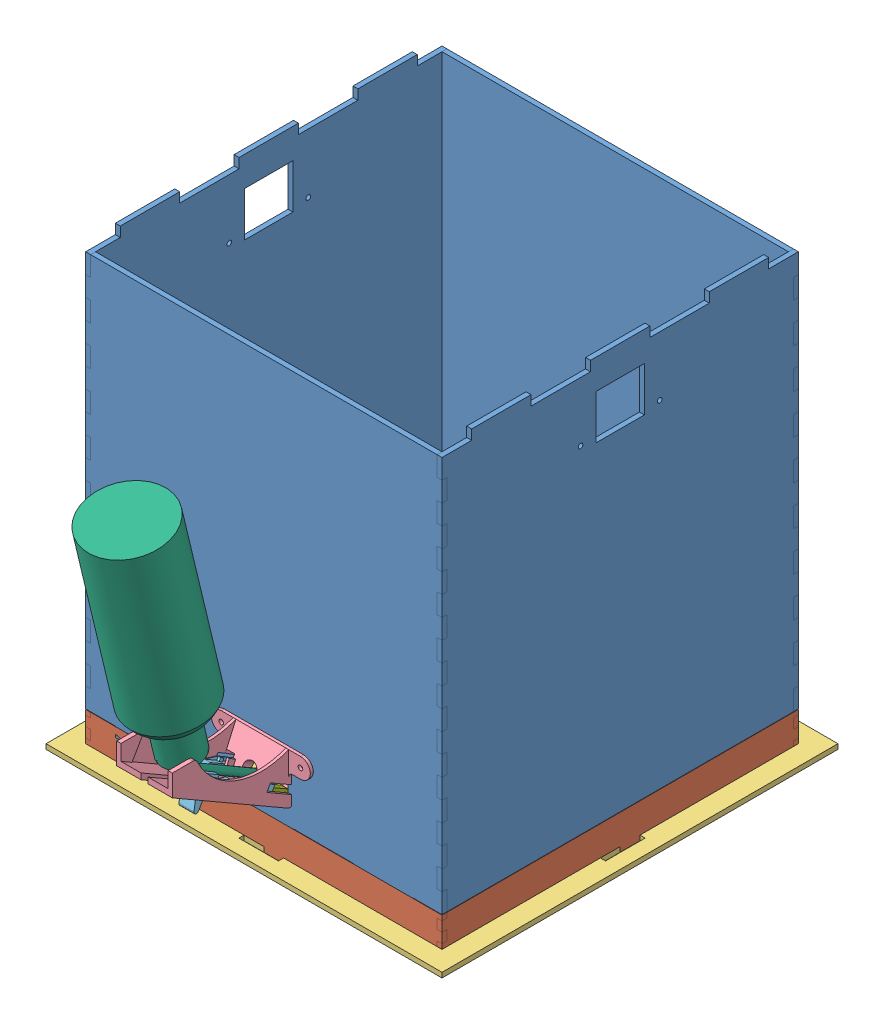
SolidWorks assembly lickometerChamberV2, configuration Default. Lengths in mm.
Overall size (254 282.83 353.42).
16 component instances, 7 part files, 14 mates.
Components (placement in the parent):
- lickometerV2_wallSide-1: lickometerV2_wallSide [Default] at (-35.9898 6.3492 13.4078) size (228.6 260.35 3.17)
- lickometerV2_wallSide-2: lickometerV2_wallSide [Default] at (-35.9898 6.3492 238.8328) size (228.6 260.35 3.17)
- bottomAssemblyV2-1: bottomAssemblyV2 [Default] at (-5.2881 -133.2401 226.0412) size (254 22.23 254)
  - bottomWall-1: bottomWall [Default] at (-30.7017 2.8103 12.7916) size (228.6 22.23 3.17)
  - bottomWall-2: bottomWall [Default] at (80.4233 2.8103 -98.3334) x (0 0 -1) z (1 0 0) size (228.6 22.23 3.17)
  - bottomWall-3: bottomWall [Default] at (-30.7017 2.8103 -209.4584) x (-1 0 0) z (0 0 -1) size (228.6 22.23 3.17)
  - bottomWall-4: bottomWall [Default] at (-141.8267 2.8103 -98.3334) x (0 0 1) z (-1 0 0) size (228.6 22.23 3.17)
  - bottomFloor-1: bottomFloor [Default] at (-30.7017 -6.7147 -98.3334) x (-1 0 0) z (0 0 1) size (254 3.17 254)
- lickometerV2_wallSide-3: lickometerV2_wallSide [Default] at (-147.1148 6.3492 127.7078) x (0 0 -1) z (-1 0 0) size (228.6 260.35 3.17)
- lickometerV2_wallSide-4: lickometerV2_wallSide [Default] at (78.3102 6.3492 127.7078) x (0 0 -1) z (-1 0 0) size (228.6 260.35 3.17)
- bottleMountAssemblyV4.0-1: bottleMountAssemblyV4.0 [Default] at (-18.3021 -116.7674 316.4884) x (-1 0 0) z (0 0 -1) size (63.5 211.04 115.3)
  - bottleMount_222103-1: bottleMount_222103 [Default] at (17.6877 34.2166 72.5756) size (63.5 56.87 79.72)
  - bottlePivot_222103-1: bottlePivot_222103 [NewBottle] at (17.6877 32.1876 37.1587) x (-1 0 0) z (0 0.5 -0.866025) size (31.26 21.51 39.37)
  - bottleV2-1: bottleV2 [Default] at (18.0978 201.5068 -12.8877) x (-0.002427 -0.231642 -0.972798) z (-0.999994 0.00306 0.001767) size (68.33 200.51 50.8)
  - irOutline_sparkfun-1: irOutline_sparkfun [Default] at (2.5302 14.6801 72.4824) x (0 0.866025 0.5) z (1 0 0) size (5 12 4.3)
  - irOutline_sparkfun-2: irOutline_sparkfun [Default] at (32.8452 14.6801 72.4824) x (0 -0.866025 -0.5) z (-1 0 0) size (5 12 4.3)
Mates (geometry in assembly coordinates):
- Coincident20: coincident aligned: plane of lickometerV2_wallSide-1 through (-35.9898 6.3492 13.4078) normal (0 0 -1); plane of bottomAssemblyV2-1/bottomWall-3 through (-35.9898 -130.4298 13.4078) normal (0 0 -1)
- Coincident27: coincident aligned: plane of lickometerV2_wallSide-1 through (-150.2898 6.3492 16.5828) normal (-1 0 0); plane of lickometerV2_wallSide-3 through (-150.2898 6.3492 127.7078) normal (-1 0 0)
- Coincident28: coincident aligned: plane of lickometerV2_wallSide-1 through (-35.9898 6.3492 13.4078) normal (0 0 -1); plane of lickometerV2_wallSide-3 through (-150.2898 6.3492 13.4078) normal (0 0 -1)
- Coincident29: coincident aligned: plane of lickometerV2_wallSide-1 through (-35.9898 133.3492 16.5828) normal (0 1 0); plane of lickometerV2_wallSide-3 through (-150.2898 133.3492 127.7078) normal (0 1 0)
- Coincident30: coincident aligned: plane of lickometerV2_wallSide-2 through (-35.9898 133.3492 242.0078) normal (0 1 0); plane of lickometerV2_wallSide-3 through (-150.2898 133.3492 127.7078) normal (0 1 0)
- Coincident31: coincident aligned: plane of lickometerV2_wallSide-3 through (-150.2898 6.3492 127.7078) normal (-1 0 0); plane of lickometerV2_wallSide-2 through (-150.2898 6.3492 242.0078) normal (-1 0 0)
- Coincident32: coincident aligned: plane of lickometerV2_wallSide-1 through (78.3102 6.3492 16.5828) normal (1 0 0); plane of lickometerV2_wallSide-4 through (78.3102 6.3492 127.7078) normal (1 0 0)
- Coincident33: coincident aligned: plane of lickometerV2_wallSide-1 through (-35.9898 6.3492 13.4078) normal (0 0 -1); plane of lickometerV2_wallSide-4 through (75.1352 6.3492 13.4078) normal (0 0 -1)
- Coincident34: coincident aligned: plane of lickometerV2_wallSide-1 through (-35.9898 133.3492 16.5828) normal (0 1 0); plane of lickometerV2_wallSide-4 through (75.1352 133.3492 127.7078) normal (0 1 0)
- Coincident35: coincident aligned: plane of lickometerV2_wallSide-2 through (-35.9898 6.3492 242.0078) normal (0 0 1); plane of lickometerV2_wallSide-3 through (-150.2898 6.3492 242.0078) normal (0 0 1)
- Coincident39: coincident aligned: plane of bottomAssemblyV2-1/bottomWall-2 through (78.3102 -130.4298 127.7078) normal (1 0 0); plane of lickometerV2_wallSide-4 through (78.3102 6.3492 127.7078) normal (1 0 0)
- Coincident40: coincident anti-aligned: plane of lickometerV2_wallSide-2 through (-35.9898 6.3492 242.0078) normal (0 0 1); plane of bottleMountAssemblyV4.0-1/bottleMount_222103-1 through (-35.9898 -82.5508 242.0078) normal (0 0 -1)
- Concentric5: concentric aligned: cylinder of lickometerV2_wallSide-2 through (-61.3898 -82.5508 238.8328) axis (0 0 1) radius 1.5; cylinder of bottleMountAssemblyV4.0-1/bottleMount_222103-1 through (-61.3898 -82.5508 242.0078) axis (0 0 1) radius 1.5
- Concentric6: concentric aligned: cylinder of lickometerV2_wallSide-2 through (-10.5898 -82.5508 238.8328) axis (0 0 1) radius 1.5; cylinder of bottleMountAssemblyV4.0-1/bottleMount_222103-1 through (-10.5898 -82.5508 242.0078) axis (0 0 1) radius 1.5
